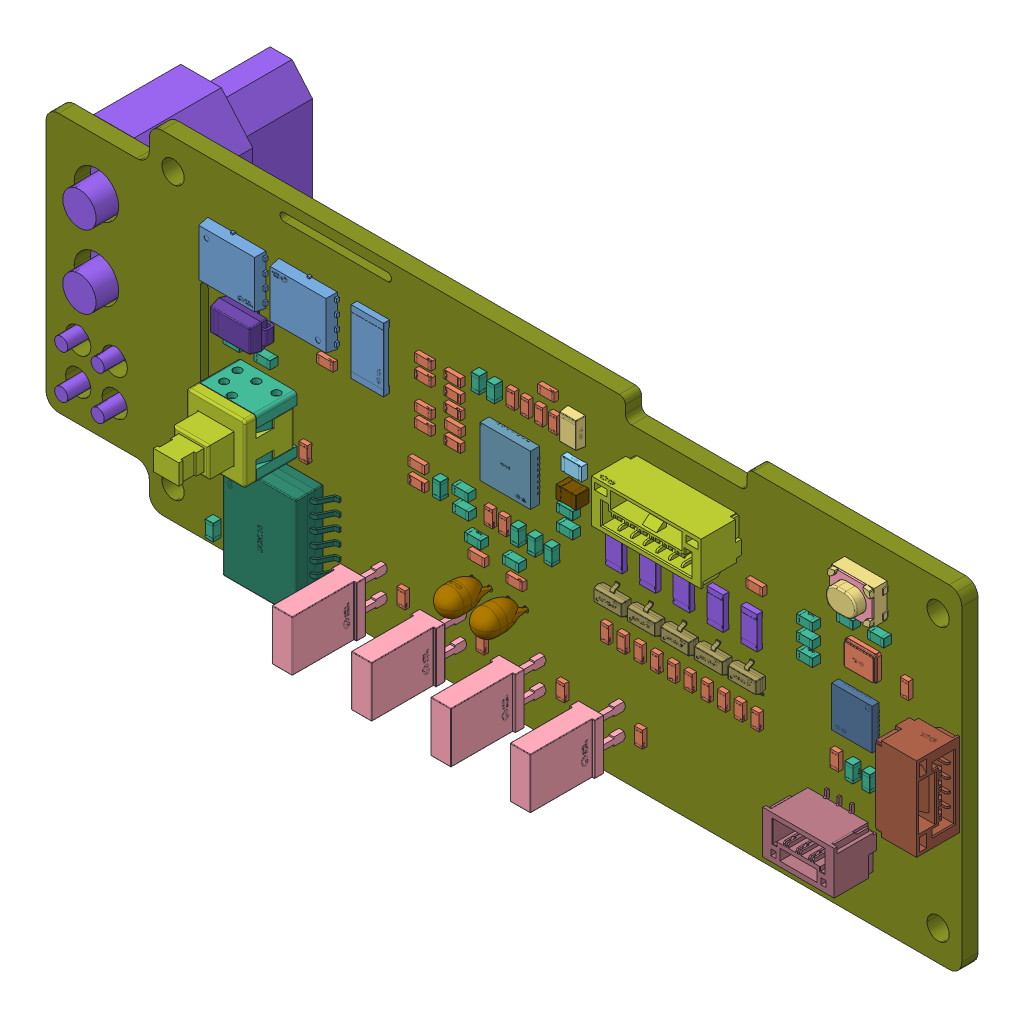
SolidWorks assembly 3D_PCB2_2026-02-08, configuration 默认. Lengths in mm.
Overall size (90.37 32.87 28.1).
162 component instances, 26 part files, 3 mates.
Components (placement in the parent):
- 3D_PCB2_2026-02-08.step-1: 3D_PCB2_2026-02-08.step [默认] at origin size (90.37 32.87 15)
  - WmRV-R84-R2512.step-1: WmRV-R84-R2512.step [默认] at (22.1172 24.7766 1.6001) x (0 1 0) z (0 0 1) size (6.3 3.2 0.61)
    - COMPOUND.step-1: COMPOUND.step [默认] at origin size (6.3 3.2 0.61)
  - WmRV-R3-R0603.step-1: WmRV-R3-R0603.step [默认] at (27.4493 25.0191 1.6001) x (-1 0 0) z (0 0 1) size (1.62 0.81 0.45)
    - COMPOUND-0.step-1: COMPOUND-0.step [默认] at origin size (1.62 0.81 0.45)
  - WmRV-R4-R0603.step-1: WmRV-R4-R0603.step [默认] at (27.4321 26.4161 1.6001) x (-1 0 0) z (0 0 1) size (1.62 0.81 0.45)
    - COMPOUND-0.step-1: COMPOUND-0.step [默认] at origin size (1.62 0.81 0.45)
  - WmRV-R5-R0603.step-1: WmRV-R5-R0603.step [默认] at (30.3531 26.4161 1.6001) size (1.62 0.81 0.45)
    - COMPOUND-0.step-1: COMPOUND-0.step [默认] at origin size (1.62 0.81 0.45)
  - WmRV-R6-R0603.step-1: WmRV-R6-R0603.step [默认] at (30.3531 25.0191 1.6001) size (1.62 0.81 0.45)
    - COMPOUND-0.step-1: COMPOUND-0.step [默认] at origin size (1.62 0.81 0.45)
  - WmRV-R8-R0603.step-1: WmRV-R8-R0603.step [默认] at (30.3853 22.1925 1.6001) size (1.62 0.81 0.45)
    - COMPOUND-0.step-1: COMPOUND-0.step [默认] at origin size (1.62 0.81 0.45)
  - WmRV-R9-R0603.step-1: WmRV-R9-R0603.step [默认] at (30.3531 20.828 1.6001) size (1.62 0.81 0.45)
    - COMPOUND-0.step-1: COMPOUND-0.step [默认] at origin size (1.62 0.81 0.45)
  - WmRV-R10-R0603.step-1: WmRV-R10-R0603.step [默认] at (27.4321 22.225 1.6001) x (-1 0 0) z (0 0 1) size (1.62 0.81 0.45)
    - COMPOUND-0.step-1: COMPOUND-0.step [默认] at origin size (1.62 0.81 0.45)
  - WmRV-R11-R0603.step-1: WmRV-R11-R0603.step [默认] at (27.4321 20.828 1.6001) x (-1 0 0) z (0 0 1) size (1.62 0.81 0.45)
    - COMPOUND-0.step-1: COMPOUND-0.step [默认] at origin size (1.62 0.81 0.45)
  - WmRV-R12-R0603.step-1: WmRV-R12-R0603.step [默认] at (33.9091 16.383 1.6001) x (0 1 0) z (0 0 1) size (1.62 0.81 0.45)
    - COMPOUND-0.step-1: COMPOUND-0.step [默认] at origin size (1.62 0.81 0.45)
  - WmRV-R13-R0603.step-1: WmRV-R13-R0603.step [默认] at (35.3061 16.383 1.6001) x (0 1 0) z (0 0 1) size (1.62 0.81 0.45)
    - COMPOUND-0.step-1: COMPOUND-0.step [默认] at origin size (1.62 0.81 0.45)
  - WmRV-R20-R0603.step-1: WmRV-R20-R0603.step [默认] at (26.8015 15.6931 1.6001) size (1.62 0.81 0.45)
    - COMPOUND-0.step-1: COMPOUND-0.step [默认] at origin size (1.62 0.81 0.45)
  - WmRV-R21-R0603.step-1: WmRV-R21-R0603.step [默认] at (26.7894 17.2153 1.6001) size (1.62 0.81 0.45)
    - COMPOUND-0.step-1: COMPOUND-0.step [默认] at origin size (1.62 0.81 0.45)
  - WmRV-R22-R0603.step-1: WmRV-R22-R0603.step [默认] at (37.4651 27.5591 1.6001) x (0 -1 0) z (0 0 1) size (1.62 0.81 0.45)
    - COMPOUND-0.step-1: COMPOUND-0.step [默认] at origin size (1.62 0.81 0.45)
  - WmRV-R23-R0603.step-1: WmRV-R23-R0603.step [默认] at (38.8621 27.5591 1.6001) x (0 -1 0) z (0 0 1) size (1.62 0.81 0.45)
    - COMPOUND-0.step-1: COMPOUND-0.step [默认] at origin size (1.62 0.81 0.45)
  - WmRV-R24-R0603.step-1: WmRV-R24-R0603.step [默认] at (36.0681 27.5591 1.6001) x (0 -1 0) z (0 0 1) size (1.62 0.81 0.45)
    - COMPOUND-0.step-1: COMPOUND-0.step [默认] at origin size (1.62 0.81 0.45)
  - WmRV-R25-R0603.step-1: WmRV-R25-R0603.step [默认] at (17.761 21.4915 1.6001) x (-1 0 0) z (0 0 1) size (1.62 0.81 0.45)
    - COMPOUND-0.step-1: COMPOUND-0.step [默认] at origin size (1.62 0.81 0.45)
  - WmRV-R26-R0603.step-1: WmRV-R26-R0603.step [默认] at (39.5952 29.8217 1.6001) x (-1 0 0) z (0 0 1) size (1.62 0.81 0.45)
    - COMPOUND-0.step-1: COMPOUND-0.step [默认] at origin size (1.62 0.81 0.45)
  - WmRV-R27-R0603.step-1: WmRV-R27-R0603.step [默认] at (40.2591 27.5591 1.6001) x (0 -1 0) z (0 0 1) size (1.62 0.81 0.45)
    - COMPOUND-0.step-1: COMPOUND-0.step [默认] at origin size (1.62 0.81 0.45)
  - WmRV-R31-R0603.step-1: WmRV-R31-R0603.step [默认] at (47.0294 12.1883 1.6001) x (0 1 0) z (0 0 1) size (1.62 0.81 0.45)
    - COMPOUND-0.step-1: COMPOUND-0.step [默认] at origin size (1.62 0.81 0.45)
  - WmRV-R32-R0603.step-1: WmRV-R32-R0603.step [默认] at (45.3784 12.1883 1.6001) x (0 1 0) z (0 0 1) size (1.62 0.81 0.45)
    - COMPOUND-0.step-1: COMPOUND-0.step [默认] at origin size (1.62 0.81 0.45)
  - WmRV-R33-R0603.step-1: WmRV-R33-R0603.step [默认] at (50.3315 12.1883 1.6001) x (0 1 0) z (0 0 1) size (1.62 0.81 0.45)
    - COMPOUND-0.step-1: COMPOUND-0.step [默认] at origin size (1.62 0.81 0.45)
  - WmRV-R34-R0603.step-1: WmRV-R34-R0603.step [默认] at (48.6804 12.1883 1.6001) x (0 1 0) z (0 0 1) size (1.62 0.81 0.45)
    - COMPOUND-0.step-1: COMPOUND-0.step [默认] at origin size (1.62 0.81 0.45)
  - WmRV-R35-R0603.step-1: WmRV-R35-R0603.step [默认] at (53.6335 12.1883 1.6001) x (0 1 0) z (0 0 1) size (1.62 0.81 0.45)
    - COMPOUND-0.step-1: COMPOUND-0.step [默认] at origin size (1.62 0.81 0.45)
  - WmRV-R36-R0603.step-1: WmRV-R36-R0603.step [默认] at (51.9825 12.1883 1.6001) x (0 1 0) z (0 0 1) size (1.62 0.81 0.45)
    - COMPOUND-0.step-1: COMPOUND-0.step [默认] at origin size (1.62 0.81 0.45)
  - WmRV-R37-R0603.step-1: WmRV-R37-R0603.step [默认] at (56.9355 12.1883 1.6001) x (0 1 0) z (0 0 1) size (1.62 0.81 0.45)
    - COMPOUND-0.step-1: COMPOUND-0.step [默认] at origin size (1.62 0.81 0.45)
  - WmRV-R38-R0603.step-1: WmRV-R38-R0603.step [默认] at (55.2845 12.1883 1.6001) x (0 1 0) z (0 0 1) size (1.62 0.81 0.45)
    - COMPOUND-0.step-1: COMPOUND-0.step [默认] at origin size (1.62 0.81 0.45)
  - WmRV-R39-R0603.step-1: WmRV-R39-R0603.step [默认] at (60.2375 12.1883 1.6001) x (0 1 0) z (0 0 1) size (1.62 0.81 0.45)
    - COMPOUND-0.step-1: COMPOUND-0.step [默认] at origin size (1.62 0.81 0.45)
  - WmRV-R40-R0603.step-1: WmRV-R40-R0603.step [默认] at (58.5865 12.1883 1.6001) x (0 1 0) z (0 0 1) size (1.62 0.81 0.45)
    - COMPOUND-0.step-1: COMPOUND-0.step [默认] at origin size (1.62 0.81 0.45)
  - WmRV-R15-R0603.step-1: WmRV-R15-R0603.step [默认] at (36.4491 12.065 1.6001) x (-1 0 0) z (0 0 1) size (1.62 0.81 0.45)
    - COMPOUND-0.step-1: COMPOUND-0.step [默认] at origin size (1.62 0.81 0.45)
  - WmRV-R17-R0603.step-1: WmRV-R17-R0603.step [默认] at (32.7017 12.2384 1.6001) size (1.62 0.81 0.45)
    - COMPOUND-0.step-1: COMPOUND-0.step [默认] at origin size (1.62 0.81 0.45)
  - WmRV-R79-R0603.step-1: WmRV-R79-R0603.step [默认] at (33.0941 5.1797 1.6001) x (0 1 0) z (0 0 1) size (1.62 0.81 0.45)
    - COMPOUND-0.step-1: COMPOUND-0.step [默认] at origin size (1.62 0.81 0.45)
  - WmRV-R80-R0603.step-1: WmRV-R80-R0603.step [默认] at (25.3019 5.1441 1.6001) x (0 1 0) z (0 0 1) size (1.62 0.81 0.45)
    - COMPOUND-0.step-1: COMPOUND-0.step [默认] at origin size (1.62 0.81 0.45)
  - WmRV-R81-R0603.step-1: WmRV-R81-R0603.step [默认] at (48.7218 4.9516 1.6001) x (0 1 0) z (0 0 1) size (1.62 0.81 0.45)
    - COMPOUND-0.step-1: COMPOUND-0.step [默认] at origin size (1.62 0.81 0.45)
  - WmRV-R82-R0603.step-1: WmRV-R82-R0603.step [默认] at (41.0176 5.0593 1.6001) x (0 1 0) z (0 0 1) size (1.62 0.81 0.45)
    - COMPOUND-0.step-1: COMPOUND-0.step [默认] at origin size (1.62 0.81 0.45)
  - WmRV-R86-R0603.step-1: WmRV-R86-R0603.step [默认] at (74.961 22.2365 1.6001) x (0 -1 0) z (0 0 1) size (1.62 0.81 0.45)
    - COMPOUND-0.step-1: COMPOUND-0.step [默认] at origin size (1.62 0.81 0.45)
  - WmRV-R85-R0603.step-1: WmRV-R85-R0603.step [默认] at (68.0472 12.6732 1.6001) x (0 -1 0) z (0 0 1) size (1.62 0.81 0.45)
    - COMPOUND-0.step-1: COMPOUND-0.step [默认] at origin size (1.62 0.81 0.45)
  - WmRV-R87-R0603.step-1: WmRV-R87-R0603.step [默认] at (15.6463 12.7266 1.6001) x (0 1 0) z (0 0 1) size (1.62 0.81 0.45)
    - COMPOUND-0.step-1: COMPOUND-0.step [默认] at origin size (1.62 0.81 0.45)
  - WmRV-R88-R0603.step-1: WmRV-R88-R0603.step [默认] at (60.1459 23.4729 1.6001) size (1.62 0.81 0.45)
    - COMPOUND-0.step-1: COMPOUND-0.step [默认] at origin size (1.62 0.81 0.45)
  - WmRV-R2-R0603.step-1: WmRV-R2-R0603.step [默认] at (30.3531 23.622 1.6001) x (-1 0 0) z (0 0 1) size (1.62 0.81 0.45)
    - COMPOUND-0.step-1: COMPOUND-0.step [默认] at origin size (1.62 0.81 0.45)
  - WmRV-SW15.step-1: WmRV-SW15.step [默认] at (70.751 28.5292 1.6001) x (-1 0 0) z (0 0 1) size (4.65 3.3 2.52)
    - SW-SMD_4P-L4.2-W3.2-P2.15-LS4.6-1.step-1: SW-SMD_4P-L4.2-W3.2-P2.15-LS4.6-1.step [默认] at origin size (4.65 3.3 2.52)
      - SOLID.step-1: SOLID.step [默认] at origin size (4.65 3.3 2.52)
      - SOLID-1.step-1: SOLID-1.step [默认] at origin size (4.2 3.3 0.19)
  - WmRV-R76-R0805.step-1: WmRV-R76-R0805.step [默认] at (42.2591 24.765 1.6001) size (2 1.3 0.61)
    - COMPOUND-2.step-1: COMPOUND-2.step [默认] at origin size (2 1.3 0.61)
  - WmRV-SW16.step-1: WmRV-SW16.step [默认] at (11.6698 14.2952 1.6001) x (-1 0 0) z (0 0 1) size (5.8 5.8 13.6)
    - SW-TH_5.8ZSGT.step-1: SW-TH_5.8ZSGT.step [默认] at origin size (5.8 5.8 13.6)
      - SOLID-3.step-1: SOLID-3.step [默认] at origin size (5.8 5.8 7.6)
      - SOLID-4.step-1: SOLID-4.step [默认] at origin size (5.8 5.8 9.74)
  - WmRV-R65-R1206.step-1: WmRV-R65-R1206.step [默认] at (49.7282 19.8084 1.6001) x (0 1 0) z (0 0 1) size (3.2 1.6 0.56)
    - COMPOUND-5.step-1: COMPOUND-5.step [默认] at origin size (3.2 1.6 0.56)
  - WmRV-R66-R1206.step-1: WmRV-R66-R1206.step [默认] at (53.062 19.8084 1.6001) x (0 1 0) z (0 0 1) size (3.2 1.6 0.56)
    - COMPOUND-5.step-1: COMPOUND-5.step [默认] at origin size (3.2 1.6 0.56)
  - WmRV-R67-R1206.step-1: WmRV-R67-R1206.step [默认] at (56.3957 19.8084 1.6001) x (0 1 0) z (0 0 1) size (3.2 1.6 0.56)
    - COMPOUND-5.step-1: COMPOUND-5.step [默认] at origin size (3.2 1.6 0.56)
  - WmRV-R68-R1206.step-1: WmRV-R68-R1206.step [默认] at (59.7295 19.8084 1.6001) x (0 1 0) z (0 0 1) size (3.2 1.6 0.56)
    - COMPOUND-5.step-1: COMPOUND-5.step [默认] at origin size (3.2 1.6 0.56)
  - WmRV-R64-R1206.step-1: WmRV-R64-R1206.step [默认] at (46.3944 19.8084 1.6001) x (0 1 0) z (0 0 1) size (3.2 1.6 0.56)
    - COMPOUND-5.step-1: COMPOUND-5.step [默认] at origin size (3.2 1.6 0.56)
  - WmRV-R16-RES-TH_L2.5-W2.5-P1.70-D0.3.step-1: WmRV-R16-RES-TH_L2.5-W2.5-P1.70-D0.3.step [默认] at (36.3221 9.906 1.6001) x (-1 0 0) z (0 0 1) size (2.52 2.5 7.2)
    - COMPOUND-6.step-1: COMPOUND-6.step [默认] at origin size (2.52 2.5 7.2)
  - WmRV-R14-RES-TH_L2.5-W2.5-P1.70-D0.3.step-1: WmRV-R14-RES-TH_L2.5-W2.5-P1.70-D0.3.step [默认] at (32.7661 9.906 1.6001) size (2.52 2.5 7.2)
    - COMPOUND-6.step-1: COMPOUND-6.step [默认] at origin size (2.52 2.5 7.2)
  - WmRV-U13-QFN-28_L4.0-W4.0-P0.40-BL-EP2.8.step-1: WmRV-U13-QFN-28_L4.0-W4.0-P0.40-BL-EP2.8.step [默认] at (70.06 17.4212 1.6001) x (-1 0 0) z (0 0 1) size (4 4 0.72)
    - COMPOUND-7.step-1: COMPOUND-7.step [默认] at origin size (4 4 0.72)
  - WmRV-U14-CONN-SMD_4P-P1.25_XUNPU_WAFER-GH1.25-4PWB.step-1: WmRV-U14-CONN-SMD_4P-P1.25_XUNPU_WAFER-GH1.25-4PWB.step [默认] at (76.8352 16.45 1.6001) x (0 1 0) z (0 0 1) size (8.25 5 4.35)
    - COMPOUND-8.step-1: COMPOUND-8.step [默认] at origin size (8.25 5 4.35)
  - WmRV-Q7-SOT-23-3_L2.9-W1.3-P1.90-LS2.4-BR.step-1: WmRV-Q7-SOT-23-3_L2.9-W1.3-P1.90-LS2.4-BR.step [默认] at (56.2111 15.5381 1.6001) x (0 -1 0) z (0 0 1) size (2.5 2.89 1.05)
    - COMPOUND-9.step-1: COMPOUND-9.step [默认] at origin size (2.5 2.89 1.05)
  - WmRV-Q8-SOT-23-3_L2.9-W1.3-P1.90-LS2.4-BR.step-1: WmRV-Q8-SOT-23-3_L2.9-W1.3-P1.90-LS2.4-BR.step [默认] at (59.5257 15.5381 1.6001) x (0 -1 0) z (0 0 1) size (2.5 2.89 1.05)
    - COMPOUND-9.step-1: COMPOUND-9.step [默认] at origin size (2.5 2.89 1.05)
  - WmRV-Q9-SOT-23-3_L2.9-W1.3-P1.90-LS2.4-BR.step-1: WmRV-Q9-SOT-23-3_L2.9-W1.3-P1.90-LS2.4-BR.step [默认] at (49.582 15.5381 1.6001) x (0 -1 0) z (0 0 1) size (2.5 2.89 1.05)
    - COMPOUND-9.step-1: COMPOUND-9.step [默认] at origin size (2.5 2.89 1.05)
  - WmRV-Q10-SOT-23-3_L2.9-W1.3-P1.90-LS2.4-BR.step-1: WmRV-Q10-SOT-23-3_L2.9-W1.3-P1.90-LS2.4-BR.step [默认] at (46.2674 15.5381 1.6001) x (0 -1 0) z (0 0 1) size (2.5 2.89 1.05)
    - COMPOUND-9.step-1: COMPOUND-9.step [默认] at origin size (2.5 2.89 1.05)
  - WmRV-Q6-SOT-23-3_L2.9-W1.3-P1.90-LS2.4-BR.step-1: WmRV-Q6-SOT-23-3_L2.9-W1.3-P1.90-LS2.4-BR.step [默认] at (52.8966 15.5381 1.6001) x (0 -1 0) z (0 0 1) size (2.5 2.89 1.05)
    - COMPOUND-9.step-1: COMPOUND-9.step [默认] at origin size (2.5 2.89 1.05)
  - WmRV-BUTTON-CONN-SMD_3P-P1.25_XUNPU_WAFER-GH1.25-3PLB.step-1: WmRV-BUTTON-CONN-SMD_3P-P1.25_XUNPU_WAFER-GH1.25-3PLB.step [默认] at (68.2638 7.662 1.6001) size (7.06 4.95 4.2)
    - COMPOUND-10.step-1: COMPOUND-10.step [默认] at origin size (7.06 4.95 4.2)
  - WmRV-U4-QFN-28_L5.0-W5.0-P0.50-TL-EP3.3.step-1: WmRV-U4-QFN-28_L5.0-W5.0-P0.50-TL-EP3.3.step [默认] at (36.0465 22.0655 1.6001) size (5 5 0.93)
    - COMPOUND-11.step-1: COMPOUND-11.step [默认] at origin size (5 5 0.93)
  - WmRV-U12-SOIC-16_L10.3-W7.5-P1.27-LS10.3-BL.step-1: WmRV-U12-SOIC-16_L10.3-W7.5-P1.27-LS10.3-BL.step [默认] at (13.7371 5.7123 1.6001) x (0 1 0) z (0 0 1) size (10.3 10.41 2.85)
    - COMPOUND-12.step-1: COMPOUND-12.step [默认] at origin size (10.3 10.41 2.85)
  - WmRV-Board.step-1: WmRV-Board.step [默认] at origin size (90.37 32.87 1.6)
  - WmRV-D2-SMA_L4.2-W2.6-LS5.0-RD_1.step-1: WmRV-D2-SMA_L4.2-W2.6-LS5.0-RD_1.step [默认] at (9.9917 21.1675 1.6001) size (5 2.57 2.05)
  - WmRV-C33-C0805.step-1: WmRV-C33-C0805.step [默认] at (42.4181 22.733 1.6001) x (-1 0 0) z (0 0 1) size (2 1.3 1.3)
  - WmRV-Q11-DFN-8_L5.8-W4.9-P1.27-LS6.1-BL-2.step-1: WmRV-Q11-DFN-8_L5.8-W4.9-P1.27-LS6.1-BL-2.step [默认] at (15.7047 25.2897 1.6001) x (0 1 0) z (0 0 1) size (5.15 6.1 1.03)
  - WmRV-Q11-DFN-8_L5.8-W4.9-P1.27-LS6.1-BL-2.step-2: WmRV-Q11-DFN-8_L5.8-W4.9-P1.27-LS6.1-BL-2.step [默认] at (8.6597 25.278 1.6001) x (0 -1 0) z (0 0 1) size (5.15 6.1 1.03)
  - WmRV-X2-CRYSTAL-SMD_4P-L3.2-W2.5-BL.step-1: WmRV-X2-CRYSTAL-SMD_4P-L3.2-W2.5-BL.step [默认] at (70.695 22.5012 1.6001) x (-1 0 0) z (0 0 1) size (3.2 2.5 0.7)
  - WmRV-D50-SOD-123FL_L2.7-W1.8-LS3.8-RD.step-1: WmRV-D50-SOD-123FL_L2.7-W1.8-LS3.8-RD.step [默认] at (42.1641 28.0671 1.6001) x (0 1 0) z (0 0 1) size (3.7 1.8 1.14)
  - WmRV-LED5-LED-TH_L5.0-W2.5-P2.54-FD_GREEN_XL-257SYGD-L.step-1: WmRV-LED5-LED-TH_L5.0-W2.5-P2.54-FD_GREEN_XL-257SYGD-L.step [默认] at (38.7774 5.207 1.6001) x (0 1 0) z (0 0 1) size (5 2.5 15)
  - WmRV-LED5-LED-TH_L5.0-W2.5-P2.54-FD_GREEN_XL-257SYGD-L.step-2: WmRV-LED5-LED-TH_L5.0-W2.5-P2.54-FD_GREEN_XL-257SYGD-L.step [默认] at (30.9457 5.207 1.6001) x (0 1 0) z (0 0 1) size (5 2.5 15)
  - WmRV-LED5-LED-TH_L5.0-W2.5-P2.54-FD_GREEN_XL-257SYGD-L.step-3: WmRV-LED5-LED-TH_L5.0-W2.5-P2.54-FD_GREEN_XL-257SYGD-L.step [默认] at (23.114 5.207 1.6001) x (0 1 0) z (0 0 1) size (5 2.5 15)
  - WmRV-LED5-LED-TH_L5.0-W2.5-P2.54-FD_GREEN_XL-257SYGD-L.step-4: WmRV-LED5-LED-TH_L5.0-W2.5-P2.54-FD_GREEN_XL-257SYGD-L.step [默认] at (46.6091 5.207 1.6001) x (0 1 0) z (0 0 1) size (5 2.5 15)
  - WmRV-D1-SOD-323_L1.6-W1.3-LS2.7-RD.step-1: WmRV-D1-SOD-323_L1.6-W1.3-LS2.7-RD.step [默认] at (45.7201 24.384 1.6001) x (0 -1 0) z (0 0 1) size (2.65 1.3 1.1)
  - WmRV-C1-C0603.step-1: WmRV-C1-C0603.step [默认] at (34.4775 27.4985 1.6001) x (0 1 0) z (0 0 1) size (1.6 0.8 0.8)
  - WmRV-C1-C0603.step-2: WmRV-C1-C0603.step [默认] at (36.4491 13.843 1.6001) x (-1 0 0) z (0 0 1) size (1.6 0.8 0.8)
  - WmRV-C1-C0603.step-3: WmRV-C1-C0603.step [默认] at (32.701 13.9081 1.6001) size (1.6 0.8 0.8)
  - WmRV-C1-C0603.step-4: WmRV-C1-C0603.step [默认] at (29.1228 16.5302 1.6001) x (0 1 0) z (0 0 1) size (1.6 0.8 0.8)
  - WmRV-C1-C0603.step-5: WmRV-C1-C0603.step [默认] at (31.453 17.3416 1.6001) x (-1 0 0) z (0 0 1) size (1.6 0.8 0.8)
  - WmRV-C1-C0603.step-6: WmRV-C1-C0603.step [默认] at (31.5108 15.777 1.6001) x (-1 0 0) z (0 0 1) size (1.6 0.8 0.8)
  - WmRV-C1-C0603.step-7: WmRV-C1-C0603.step [默认] at (38.4811 16.383 1.6001) x (0 1 0) z (0 0 1) size (1.6 0.8 0.8)
  - WmRV-C1-C0603.step-8: WmRV-C1-C0603.step [默认] at (40.1321 16.383 1.6001) x (0 1 0) z (0 0 1) size (1.6 0.8 0.8)
  - WmRV-C1-C0603.step-9: WmRV-C1-C0603.step [默认] at (41.7831 19.304 1.6001) x (-1 0 0) z (0 0 1) size (1.6 0.8 0.8)
  - WmRV-C1-C0603.step-10: WmRV-C1-C0603.step [默认] at (41.7831 20.955 1.6001) x (-1 0 0) z (0 0 1) size (1.6 0.8 0.8)
  - WmRV-C1-C0603.step-11: WmRV-C1-C0603.step [默认] at (36.8302 16.383 1.6001) x (0 1 0) z (0 0 1) size (1.6 0.8 0.8)
  - WmRV-C1-C0603.step-12: WmRV-C1-C0603.step [默认] at (8.8836 18.8768 1.6001) x (-1 0 0) z (0 0 1) size (1.6 0.8 0.8)
  - WmRV-C1-C0603.step-13: WmRV-C1-C0603.step [默认] at (11.9171 18.9097 1.6001) x (-1 0 0) z (0 0 1) size (1.6 0.8 0.8)
  - WmRV-C1-C0603.step-14: WmRV-C1-C0603.step [默认] at (65.4491 20.2385 1.6001) size (1.6 0.8 0.8)
  - WmRV-C1-C0603.step-15: WmRV-C1-C0603.step [默认] at (72.473 25.4222 1.6001) x (-1 0 0) z (0 0 1) size (1.6 0.8 0.8)
  - WmRV-C1-C0603.step-16: WmRV-C1-C0603.step [默认] at (69.425 25.4222 1.6001) x (-1 0 0) z (0 0 1) size (1.6 0.8 0.8)
  - WmRV-C1-C0603.step-17: WmRV-C1-C0603.step [默认] at (65.4491 23.2865 1.6001) size (1.6 0.8 0.8)
  - WmRV-C1-C0603.step-18: WmRV-C1-C0603.step [默认] at (65.4491 21.7625 1.6001) x (-1 0 0) z (0 0 1) size (1.6 0.8 0.8)
  - WmRV-C1-C0603.step-19: WmRV-C1-C0603.step [默认] at (69.8501 12.7 1.6001) x (0 -1 0) z (0 0 1) size (1.6 0.8 0.8)
  - WmRV-C1-C0603.step-20: WmRV-C1-C0603.step [默认] at (20.6738 1.8052 1.6001) x (0 -1 0) z (0 0 1) size (1.6 0.8 0.8)
  - WmRV-C1-C0603.step-21: WmRV-C1-C0603.step [默认] at (6.7038 1.8052 1.6001) x (0 1 0) z (0 0 1) size (1.6 0.8 0.8)
  - WmRV-C1-C0603.step-22: WmRV-C1-C0603.step [默认] at (71.5101 12.7137 1.6001) x (0 -1 0) z (0 0 1) size (1.6 0.8 0.8)
  - WmRV-C1-C0603.step-23: WmRV-C1-C0603.step [默认] at (32.9535 27.4985 1.6001) x (0 1 0) z (0 0 1) size (1.6 0.8 0.8)
  - WmRV-U6-CONN-SMD_6P-P1.25_XUNPU_WAFER-GH1.25-6PLB.step-1: WmRV-U6-CONN-SMD_6P-P1.25_XUNPU_WAFER-GH1.25-6PLB.step [默认] at (53.0861 25.7811 1.6001) x (-1 0 0) z (0 0 1) size (10.8 4.94 4.03)
- XT60-2+4-1: XT60-2+4 [默认] at (0.0127 3.6627 0) x (-1 0 0) z (0 -1 0) size (10.2 19.9 25.6)
Mates (geometry in assembly coordinates):
- 重合1: coincident: plane of 3D_PCB2_2026-02-08.step-1/WmRV-Board.step-1 through (35.8413 16.5376 0) normal (0 0 -1); plane of XT60-2+4-1 through (0.0127 3.6627 0) normal (0 0 1)
- 重合2: coincident: plane of 3D_PCB2_2026-02-08.step-1/WmRV-Board.step-1 through (-10.1873 4.9 0) normal (-1 0 0); plane of XT60-2+4-1 through (-10.1873 3.6627 -8.6) normal (-1 0 0)
- 重合3: coincident aligned: plane of 3D_PCB2_2026-02-08.step-1/WmRV-Board.step-1 through (-1.2499 3.6627 0) normal (0 -1 0); plane of XT60-2+4-1 through (0.0127 3.6627 -8.6) normal (0 -1 0)
